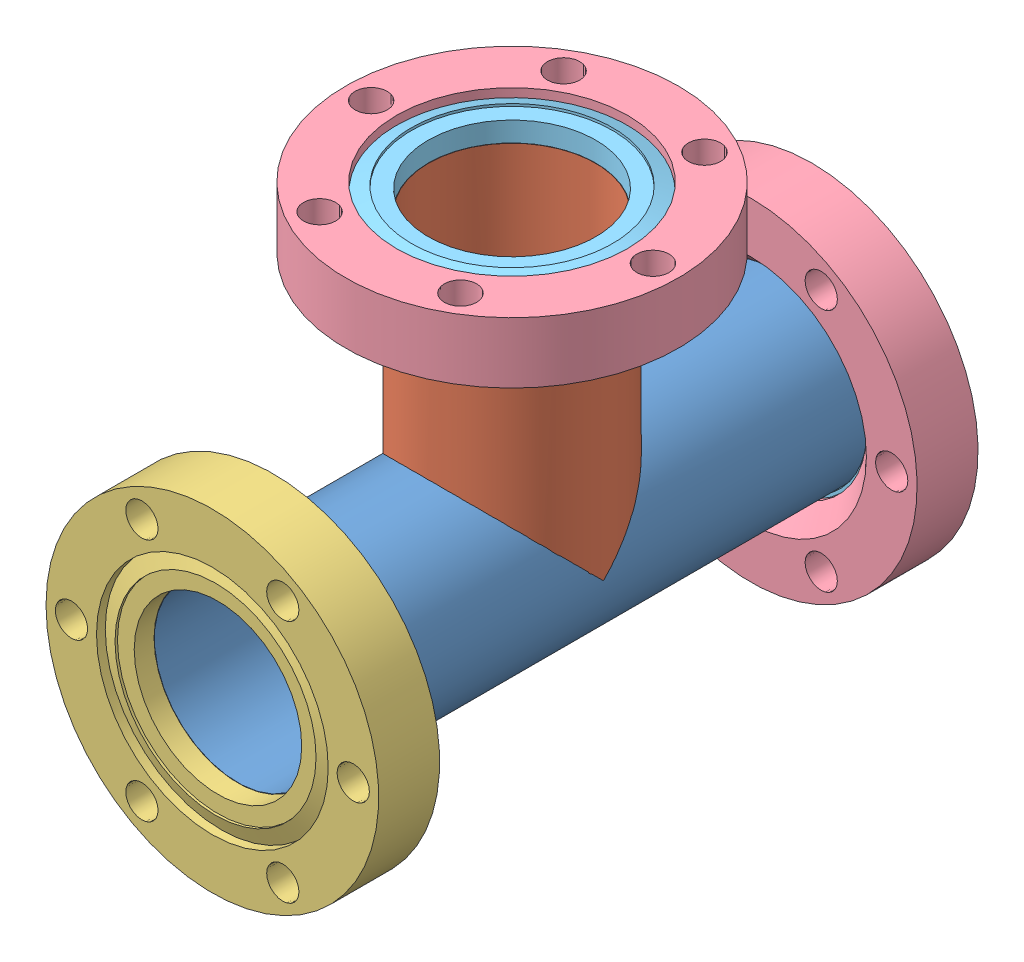
SolidWorks assembly 2.75 Tee_404002, configuration Default. Lengths in mm.
Overall size (69.34 97.13 124.92).
9 component instances, 5 part files, 0 mates.
Components (placement in the parent):
- 404002 P5_404002-001-1: 404002 P5_404002-001 [Default] at origin size (38.1 38.1 114.3)
- 404002 P6_404002-002-1: 404002 P6_404002-002 [Default] at (0 0 57.15) x (-1 0 0) z (0 1 0) size (38.1 38.1 58.86)
- 404002 P4_110014 (2.75 X 1.5 NR)_1-1: 404002 P4_110014 (2.75 X 1.5 NR)_1 [Default] at (0 0 113.2586) x (0 0 1) z (-1 0 0) size (12.7 69.34 69.34)
- 404002 P2_100014 (2.75 X 1.5 R)-1: 404002 P2_100014 (2.75 X 1.5 R) [Default] at (0 62.4586 57.15) x (0 -1 0) z (1 0 0) size (12.7 69.34 69.34)
  - 404002 P3_100014 (2.75 X 1.5 REC)-1: 404002 P3_100014 (2.75 X 1.5 REC) [Default] at origin size (12.7 69.34 69.34)
  - 404002 P1_100014 (2.75 X 1.5 INS)-1: 404002 P1_100014 (2.75 X 1.5 INS) [Default] at (1.17 0 0) x (1 0 0) z (0 0.994423 -0.105464) size (6.96 48.1 48.1)
- 404002 P2_100014 (2.75 X 1.5 R)-2: 404002 P2_100014 (2.75 X 1.5 R) [Default] at (0 0 -5.3086) x (0 0 1) z (-1 0 0) size (12.7 69.34 69.34)
  - 404002 P3_100014 (2.75 X 1.5 REC)-1: 404002 P3_100014 (2.75 X 1.5 REC) [Default] at origin size (12.7 69.34 69.34)
  - 404002 P1_100014 (2.75 X 1.5 INS)-1: 404002 P1_100014 (2.75 X 1.5 INS) [Default] at (1.17 0 0) x (1 0 0) z (0 0.994423 -0.105464) size (6.96 48.1 48.1)
